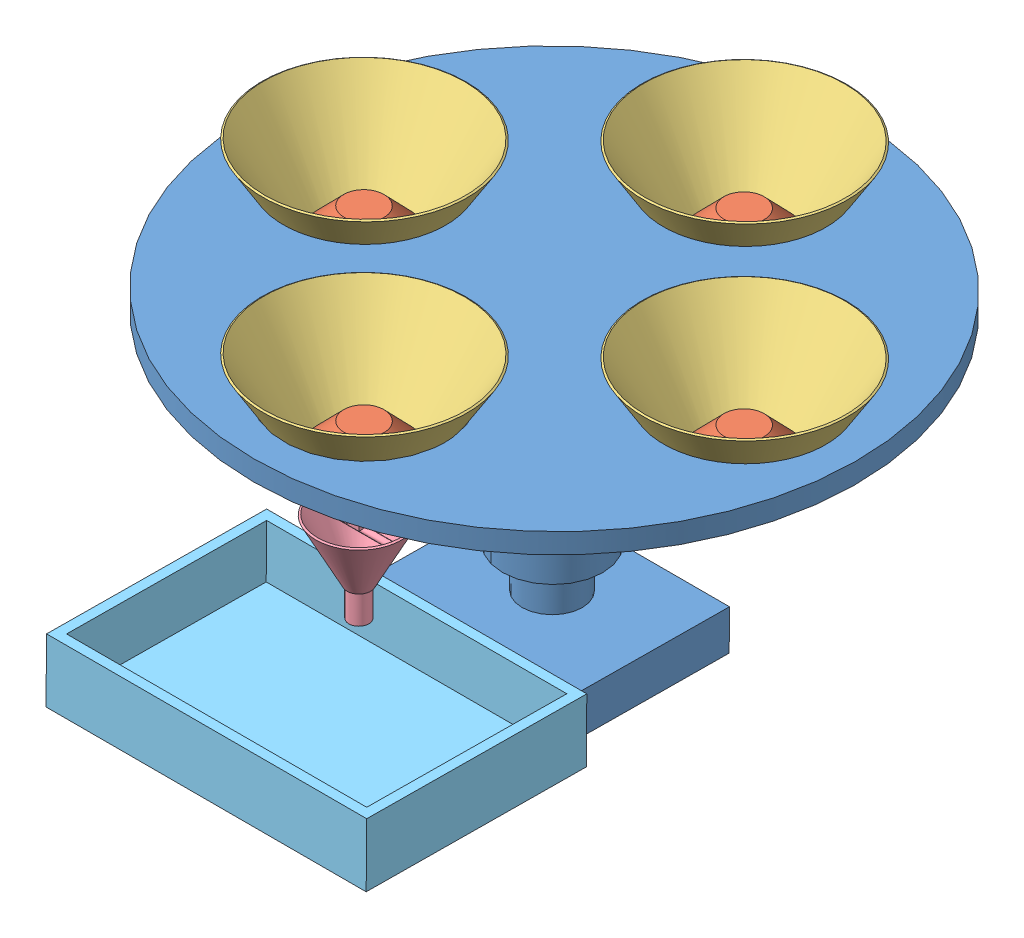
SolidWorks assembly fullChamber_base_assembly, configuration Default. Lengths in mm.
Overall size (300 175.31 303.49).
15 component instances, 5 part files, 4 mates.
Components (placement in the parent):
- Chamber_base-1: Chamber_base [Default] at (126.4444 245.6617 211.9407) x (1 0 0) z (0 0.999962 -0.008727) size (300 300 150)
- Chamber_assembly-1: Chamber_assembly [Default] at (43.496 218.9966 309.7595) x (1 0 0) z (0 0.008727 0.999962) size (101.7 65.5 101.7)
  - Chamber_inner-1: Chamber_inner [Default] at (82.9484 -5.4055 -2.5823) x (0.24578 0 0.969326) z (-0.969326 0 0.24578) size (45.64 33 45.64)
  - Chamber_outer-1: Chamber_outer [Default] at (82.9484 -8.8738 -2.5823) size (101.7 65.5 101.7)
- Chamber_assembly-2: Chamber_assembly [Default] at (-51.504 217.1182 214.7722) x (1 0 0) z (0 0.008727 0.999962) size (101.7 65.5 101.7)
  - Chamber_inner-1: Chamber_inner [Default] at (82.9484 -5.4055 -2.5823) x (0.24578 0 0.969326) z (-0.969326 0 0.24578) size (45.64 33 45.64)
  - Chamber_outer-1: Chamber_outer [Default] at (82.9484 -8.8738 -2.5823) size (101.7 65.5 101.7)
- Chamber_assembly-3: Chamber_assembly [Default] at (43.496 216.1675 119.7769) x (1 0 0) z (0 0.008727 0.999962) size (101.7 65.5 101.7)
  - Chamber_inner-1: Chamber_inner [Default] at (82.9484 -5.4055 -2.5823) x (0.24578 0 0.969326) z (-0.969326 0 0.24578) size (45.64 33 45.64)
  - Chamber_outer-1: Chamber_outer [Default] at (82.9484 -8.8738 -2.5823) size (101.7 65.5 101.7)
- Chamber_assembly-4: Chamber_assembly [Default] at (138.496 217.2644 214.771) x (1 0 0) z (0 0.008727 0.999962) size (101.7 65.5 101.7)
  - Chamber_inner-1: Chamber_inner [Default] at (82.9484 -5.4055 -2.5823) x (0.24578 0 0.969326) z (-0.969326 0 0.24578) size (45.64 33 45.64)
  - Chamber_outer-1: Chamber_outer [Default] at (82.9484 -8.8738 -2.5823) size (101.7 65.5 101.7)
- Dispensing cone-1: Dispensing cone [Default] at (124.4652 174.9941 307.5254) size (42.88 47.54 42.88)
- weighing_machine-1: weighing_machine [Default] at (105.9198 100.6836 310.347) x (1 0 0) z (0 0.999962 -0.008727) size (160 110 31.51)
Mates (geometry in assembly coordinates):
- Concentric1: concentric aligned: cylinder of Chamber_base-1 through (126.4444 256.4903 306.8498) axis (0 -0.999962 0.008727) radius 40; cone of Chamber_assembly-1/Chamber_outer-1 through (126.4444 209.5764 307.2592) axis (0 -0.999962 0.008727)
- Concentric2: concentric aligned: cylinder of Chamber_base-1 through (221.4444 255.6613 211.8534) axis (0 -0.999962 0.008727) radius 40; cone of Chamber_assembly-4/Chamber_outer-1 through (221.4444 207.8441 212.2707) axis (0 -0.999962 0.008727)
- Concentric3: concentric aligned: cylinder of Chamber_base-1 through (126.4444 254.8323 116.8571) axis (0 -0.999962 0.008727) radius 40; cone of Chamber_assembly-3/Chamber_outer-1 through (126.4444 206.7472 117.2767) axis (0 -0.999962 0.008727)
- Concentric4: concentric aligned: cylinder of Chamber_base-1 through (31.4444 255.6613 211.8534) axis (0 -0.999962 0.008727) radius 40; cone of Chamber_assembly-2/Chamber_outer-1 through (31.4444 207.698 212.272) axis (0 -0.999962 0.008727)
